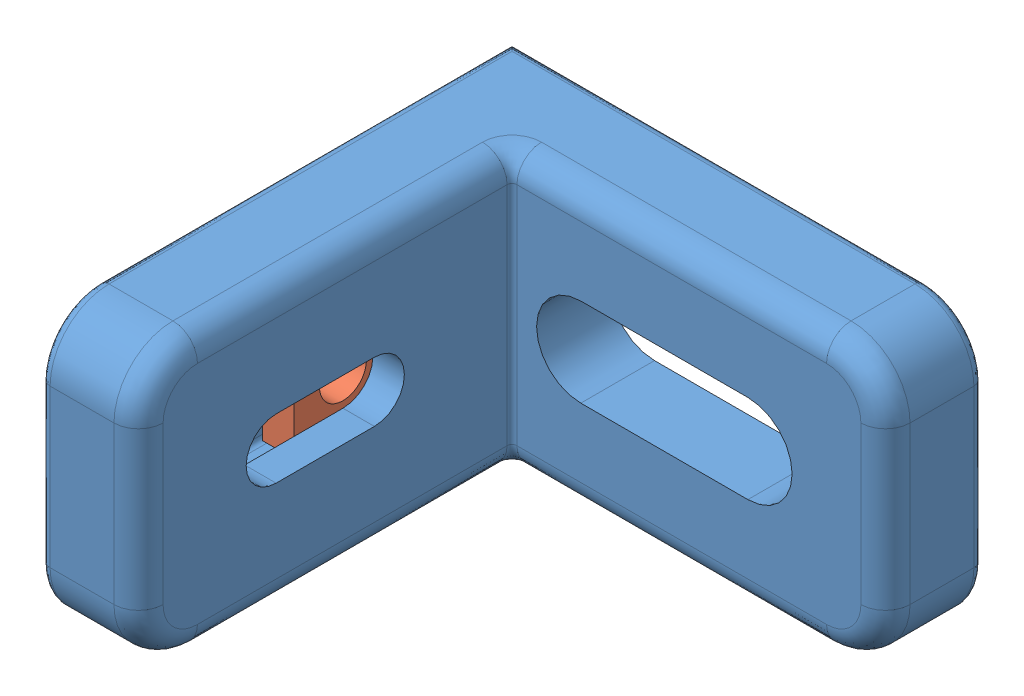
SolidWorks assembly t_slot_fastener, configuration Default. Lengths in mm.
Overall size (48 28 48).
2 component instances, 2 part files, 2 mates.
Components (placement in the parent):
- t_slot_fastener_bracket-1: t_slot_fastener_bracket [Default] at (-5.6048 8.9553 14.0143) size (48 28 48)
- t_slot_fastener_slide-1: t_slot_fastener_slide [Default] at (-5.4048 8.9553 4.0143) size (3.2 10 10)
Mates (geometry in assembly coordinates):
- Concentric1: concentric: cylinder of t_slot_fastener_bracket-1 through (42.3952 22.9553 38.0143) axis (-1 0 0) radius 3.05; cylinder of t_slot_fastener_slide-1 through (-1.1956 22.9553 38.0143) axis (-1 0 0) radius 2.3865
- Coincident1: coincident anti-aligned: plane of t_slot_fastener_bracket-1 through (1.1952 28.3053 55.0143) normal (-1 0 0); plane of t_slot_fastener_slide-1 through (1.1952 8.9553 4.0143) normal (1 0 0)
